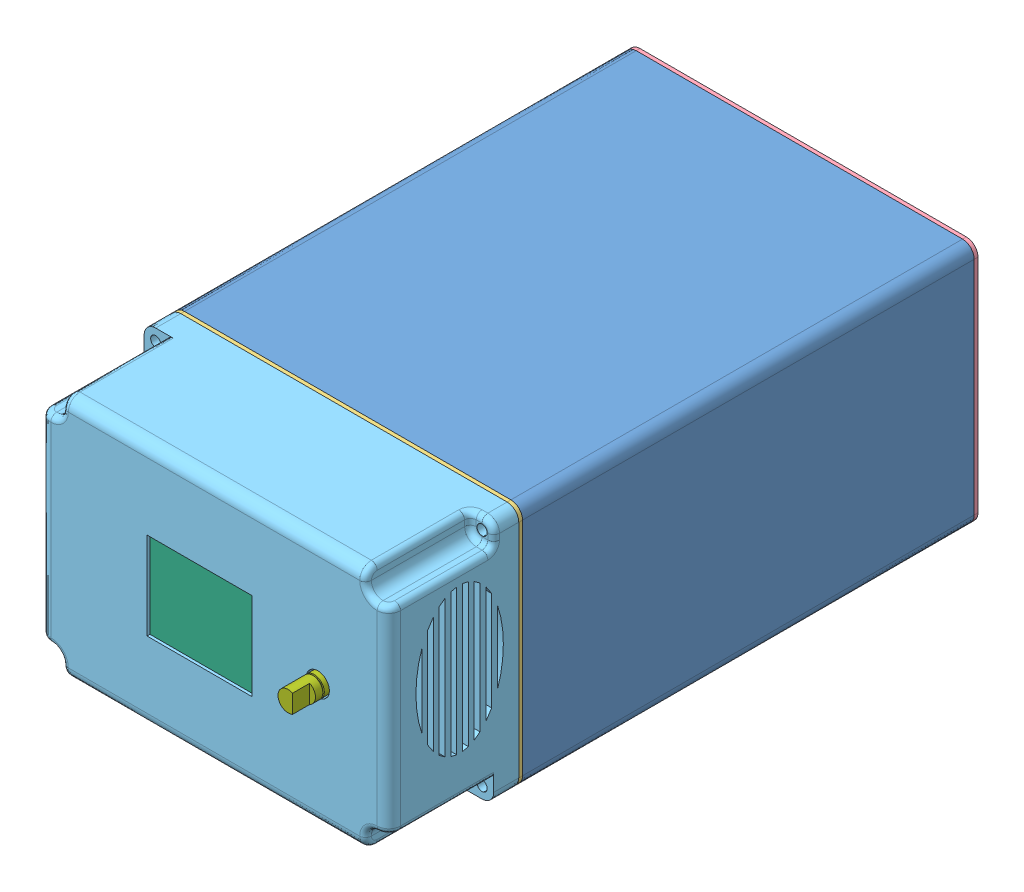
SolidWorks assembly Assembly, configuration Default. Lengths in mm.
Overall size (120 84 212.37).
86 component instances, 26 part files, 29 mates.
Components (placement in the parent):
- ProjectBox-1: ProjectBox [Default] at (98.818 101.4057 83.4216) size (120 84 155)
- Heater700W-1: Heater700W [Default] at (98.818 110.9057 242.9216) x (1 0 0) z (0 0 -1) size (43.19 37.4 149.1)
- SidePlate1-1: SidePlate1 [Default] at (98.818 101.4057 238.4216) x (1 0 0) z (0 -1 0) size (120 1.3 84)
- SidePlate2-1: SidePlate2 [Default] at (98.818 101.4057 82.1216) x (1 0 0) z (0 -1 0) size (120 1.3 84)
- Fan_Assembly-1: Fan_Assembly [По умолчанию] at (98.818 110.6057 93.4216) x (1 0 0) z (0 -1 0) size (62.65 20.13 63.06)
  - Fan_Case-1: Fan_Case [По умолчанию] at origin size (60 20.13 60)
  - Fan-1: Fan [По умолчанию] at (0 -5 0) size (62.65 17 63.06)
- ReflowControllerREV1-1: ReflowControllerREV1 [Default] at (316.3869 204.5107 265.7216) x (-1 0 0) z (0 0 -1) size (81.15 60.96 18.6)
  - ReflowControllerREV1.step-1: ReflowControllerREV1.step [Default] at origin size (81.15 60.96 18.6)
    - R_Axial_DIN0207_L6.3mm_D2.5mm_P10.16mm_Horizontal.step-1: R_Axial_DIN0207_L6.3mm_D2.5mm_P10.16mm_Horizontal.step [Default] at (251.46 -86.995 1.65) x (-1 0 0) z (0 0 1) size (10.76 2.5 5.5)
      - SOLID.step-1: SOLID.step [Default] at origin size (10.76 2.5 5.5)
    - R_Axial_DIN0207_L6.3mm_D2.5mm_P10.16mm_Horizontal.step-2: R_Axial_DIN0207_L6.3mm_D2.5mm_P10.16mm_Horizontal.step [Default] at (251.46 -83.185 1.65) x (-1 0 0) z (0 0 1) size (10.76 2.5 5.5)
      - SOLID.step-1: SOLID.step [Default] at origin size (10.76 2.5 5.5)
    - Terminal5mmx2.step-1: Terminal5mmx2.step [Default] at (255.095 -100.155 1.65) x (1 0 0) z (0 -1 0) size (8.15 13.5 10.57)
      - SOLID-0.step-1: SOLID-0.step [Default] at origin size (8.15 13.5 10.57)
    - Terminal5mmx2.step-2: Terminal5mmx2.step [Default] at (255.595 -113.49 1.65) x (1 0 0) z (0 -1 0) size (8.15 13.5 10.57)
      - SOLID-0.step-1: SOLID-0.step [Default] at origin size (8.15 13.5 10.57)
    - PinSocket_1x08_P2.54mm_Horizontal.step-1: PinSocket_1x08_P2.54mm_Horizontal.step [Default] at (185.42 -121.92 -0.05) x (1 0 0) z (0 0 -1) size (10.13 20.32 5.84)
      - SOLID-1.step-1: SOLID-1.step [Default] at origin size (10.13 20.32 5.84)
    - PinSocket_1x05_P2.54mm_Horizontal.step-1: PinSocket_1x05_P2.54mm_Horizontal.step [Default] at (185.42 -95.25 -0.05) x (1 0 0) z (0 0 -1) size (10.13 12.7 5.84)
      - SOLID-2.step-1: SOLID-2.step [Default] at origin size (10.13 12.7 5.84)
    - SOIC-8_3,9x4,9.step-1: SOIC-8_3,9x4,9.step [Default] at (213.36 -82.804 1.65) x (0 1 0) z (0 0 1) size (4.9 6 1.75)
      - SOLID-3.step-1: SOLID-3.step [Default] at origin size (4.9 6 1.75)
    - DIP-6_W7.62mm.step-1: DIP-6_W7.62mm.step [Default] at (234.95 -91.948 1.65) x (-1 0 0) z (0 0 1) size (7.87 7.05 6.98)
      - SOLID-4.step-1: SOLID-4.step [Default] at origin size (7.87 7.05 6.98)
    - Arduino_nano.step-1: Arduino_nano.step [Default] at (192.024 -90.932 3.15) x (0 -1 0) z (-1 0 0) size (45.01 18.6 18)
      - COMPOUND.step-1: COMPOUND.step [Default] at origin size (45.01 18.6 18)
    - PinHeader_1x02_P2.54mm_Vertical.step-1: PinHeader_1x02_P2.54mm_Vertical.step [Default] at (198.12 -75.692 1.65) x (0 1 0) z (0 0 1) size (2.54 5.08 11.54)
      - SOLID-5.step-1: SOLID-5.step [Default] at origin size (2.54 5.08 11.54)
    - C_Elec_4x5.8.step-1: C_Elec_4x5.8.step [Default] at (203.2 -83.312 1.65) size (5.74 5.46 5.8)
      - COMPOUND-6.step-1: COMPOUND-6.step [Default] at origin size (5.74 5.46 5.8)
    - C_0805_2012Metric.step-1: C_0805_2012Metric.step [Default] at (204.216 -91.948 1.65) x (0 -1 0) z (0 0 1) size (2 1.25 1.25)
      - SOLID-7.step-1: SOLID-7.step [Default] at origin size (2 1.25 1.25)
    - C_0805_2012Metric.step-2: C_0805_2012Metric.step [Default] at (238.252 -96.012 1.65) x (0 1 0) z (0 0 1) size (2 1.25 1.25)
      - SOLID-7.step-1: SOLID-7.step [Default] at origin size (2 1.25 1.25)
    - C_0805_2012Metric.step-3: C_0805_2012Metric.step [Default] at (219.456 -77.216 1.65) x (0 -1 0) z (0 0 1) size (2 1.25 1.25)
      - SOLID-7.step-1: SOLID-7.step [Default] at origin size (2 1.25 1.25)
    - C_Elec_4x5.8.step-2: C_Elec_4x5.8.step [Default] at (223.012 -82.296 1.65) x (-1 0 0) z (0 0 1) size (5.74 5.46 5.8)
      - COMPOUND-6.step-1: COMPOUND-6.step [Default] at origin size (5.74 5.46 5.8)
    - D_DO-41_SOD81_P10.16mm_Horizontal.step-1: D_DO-41_SOD81_P10.16mm_Horizontal.step [Default] at (212.344 -87.884 1.65) size (10.96 2.72 5.71)
      - SOLID-8.step-1: SOLID-8.step [Default] at origin size (10.96 2.72 5.71)
    - DIP-6_W7.62mm.step-2: DIP-6_W7.62mm.step [Default] at (227.584 -105.664 1.65) size (7.87 7.05 6.98)
      - SOLID-4.step-1: SOLID-4.step [Default] at origin size (7.87 7.05 6.98)
    - JST_EH_B2B-EH-A_1x02_P2.50mm_Vertical.step-1: JST_EH_B2B-EH-A_1x02_P2.50mm_Vertical.step [Default] at (210.82 -75.692 1.65) size (7.5 3.8 9.2)
      - SOLID-9.step-1: SOLID-9.step [Default] at origin size (7.5 3.8 9.2)
    - PinHeader_1x02_P2.54mm_Vertical.step-2: PinHeader_1x02_P2.54mm_Vertical.step [Default] at (223.012 -75.692 1.65) x (0 1 0) z (0 0 1) size (2.54 5.08 11.54)
      - SOLID-5.step-1: SOLID-5.step [Default] at origin size (2.54 5.08 11.54)
    - R_0805_2012Metric.step-1: R_0805_2012Metric.step [Default] at (214.376 -94.488 1.65) x (-1 0 0) z (0 0 1) size (2 1.2 0.45)
      - SOLID-10.step-1: SOLID-10.step [Default] at origin size (2 1.2 0.45)
    - R_0805_2012Metric.step-2: R_0805_2012Metric.step [Default] at (216.916 -91.44 1.65) size (2 1.2 0.45)
      - SOLID-10.step-1: SOLID-10.step [Default] at origin size (2 1.2 0.45)
    - R_0805_2012Metric.step-3: R_0805_2012Metric.step [Default] at (241.3 -99.568 1.65) size (2 1.2 0.45)
      - SOLID-10.step-1: SOLID-10.step [Default] at origin size (2 1.2 0.45)
    - R_0805_2012Metric.step-4: R_0805_2012Metric.step [Default] at (238.252 -103.632 1.65) x (0 1 0) z (0 0 1) size (2 1.2 0.45)
      - SOLID-10.step-1: SOLID-10.step [Default] at origin size (2 1.2 0.45)
    - R_0805_2012Metric.step-5: R_0805_2012Metric.step [Default] at (224.028 -105.664 1.65) size (2 1.2 0.45)
      - SOLID-10.step-1: SOLID-10.step [Default] at origin size (2 1.2 0.45)
    - R_0805_2012Metric.step-6: R_0805_2012Metric.step [Default] at (194.945 -117.475 1.65) x (0 1 0) z (0 0 1) size (2 1.2 0.45)
      - SOLID-10.step-1: SOLID-10.step [Default] at origin size (2 1.2 0.45)
    - R_0805_2012Metric.step-7: R_0805_2012Metric.step [Default] at (197.485 -112.395 -0.05) x (1 0 0) z (0 0 -1) size (2 1.2 0.45)
      - SOLID-10.step-1: SOLID-10.step [Default] at origin size (2 1.2 0.45)
    - R_0805_2012Metric.step-8: R_0805_2012Metric.step [Default] at (203.835 -122.555 1.65) x (-1 0 0) z (0 0 1) size (2 1.2 0.45)
      - SOLID-10.step-1: SOLID-10.step [Default] at origin size (2 1.2 0.45)
    - R_0805_2012Metric.step-9: R_0805_2012Metric.step [Default] at (200.66 -119.38 1.65) size (2 1.2 0.45)
      - SOLID-10.step-1: SOLID-10.step [Default] at origin size (2 1.2 0.45)
    - R_0805_2012Metric.step-10: R_0805_2012Metric.step [Default] at (201.168 -104.648 -0.05) x (1 0 0) z (0 0 -1) size (2 1.2 0.45)
      - SOLID-10.step-1: SOLID-10.step [Default] at origin size (2 1.2 0.45)
    - R_0805_2012Metric.step-11: R_0805_2012Metric.step [Default] at (200.66 -110.236 -0.05) x (1 0 0) z (0 0 -1) size (2 1.2 0.45)
      - SOLID-10.step-1: SOLID-10.step [Default] at origin size (2 1.2 0.45)
    - R_0805_2012Metric.step-12: R_0805_2012Metric.step [Default] at (197.485 -123.19 -0.05) x (-1 0 0) z (0 0 -1) size (2 1.2 0.45)
      - SOLID-10.step-1: SOLID-10.step [Default] at origin size (2 1.2 0.45)
    - R_0805_2012Metric.step-13: R_0805_2012Metric.step [Default] at (195.58 -128.905 -0.05) x (0 -1 0) z (0 0 -1) size (2 1.2 0.45)
      - SOLID-10.step-1: SOLID-10.step [Default] at origin size (2 1.2 0.45)
    - R_0805_2012Metric.step-14: R_0805_2012Metric.step [Default] at (196.215 -114.3 1.65) size (2 1.2 0.45)
      - SOLID-10.step-1: SOLID-10.step [Default] at origin size (2 1.2 0.45)
    - R_0805_2012Metric.step-15: R_0805_2012Metric.step [Default] at (200.66 -115.316 -0.05) x (1 0 0) z (0 0 -1) size (2 1.2 0.45)
      - SOLID-10.step-1: SOLID-10.step [Default] at origin size (2 1.2 0.45)
    - TO-220-3_Horizontal_TabUp.step-1: TO-220-3_Horizontal_TabUp.step [Default] at (244.475 -92.71 -0.05) x (-1 0 0) z (0 0 -1) size (10.25 19.74 12.58)
      - SOLID-11.step-1: SOLID-11.step [Default] at origin size (10.25 19.74 12.58)
    - TO-263-3_TabPin4.step-1: TO-263-3_TabPin4.step [Default] at (218.44 -99.06 -0.05) x (0 -1 0) z (0 0 -1) size (15 10 4.42)
      - SOLID-12.step-1: SOLID-12.step [Default] at origin size (15 10 4.42)
    - COMPOUND-13.step-1: COMPOUND-13.step [Default] at origin size (73.66 60.96 1.6)
- ElectronicsCover-1: ElectronicsCover [Default] at (91.628 101.3957 280.9216) size (120 84 44.6)
- TFT_1.8_128x160-1: TFT_1.8_128x160 [Default] at (91.668 101.3857 279.7216) x (0 -1 0) z (-1 0 0) size (35 3.6 56)
- Encoder-1: Encoder [Default] at (135.788 104.5957 273.6216) x (0 -1 0) z (-1 0 0) size (26.4 20.87 18.5)
- XT-60_Macho-1: XT-60_Macho [Valor predeterminado] at (55.018 70.3339 251.3773) x (0 0 1) z (-1 0 0) size (16.3 8.2 16.2)
Mates (geometry in assembly coordinates):
- Parallel2: parallel aligned: plane of ProjectBox-1 through (98.818 101.4057 238.4216) normal (0 0 1); plane of Heater700W-1 through (98.818 110.9057 242.9216) normal (0 0 1)
- Parallel3: parallel aligned: plane of ProjectBox-1 through (38.818 143.4057 238.4216) normal (0 1 0); plane of Heater700W-1 through (88.0215 129.6057 239.7216) normal (0 1 0)
- Parallel4: parallel aligned: plane of ProjectBox-1 through (98.818 101.4057 238.4216) normal (0 0 1); plane of SidePlate1-1 through (154.818 63.4057 239.7216) normal (0 0 1)
- Coincident11: coincident aligned: plane of ProjectBox-1 through (38.818 143.4057 238.4216) normal (0 1 0); plane of SidePlate1-1 through (42.818 143.4057 239.7216) normal (0 1 0)
- Coincident12: coincident aligned: plane of ProjectBox-1 through (158.818 59.4057 238.4216) normal (1 0 0); plane of SidePlate1-1 through (158.818 63.4057 239.7216) normal (1 0 0)
- Coincident13: coincident anti-aligned: plane of ProjectBox-1 through (98.818 101.4057 238.4216) normal (0 0 1); plane of SidePlate1-1 through (154.818 63.4057 238.4216) normal (0 0 -1)
- Concentric2: concentric aligned: cylinder of Heater700W-1 through (98.818 110.9057 227.5216) axis (0 0 1) radius 15.135; cylinder of SidePlate1-1 through (98.818 110.9057 238.4216) axis (0 0 1) radius 16.25
- Coincident14: coincident: line of Heater700W-1 through (109.6144 92.2057 239.7216) axis (-1 0 0); plane of SidePlate1-1 through (154.818 63.4057 239.7216) normal (0 0 1)
- Coincident18: coincident anti-aligned: plane of ProjectBox-1 through (98.818 101.4057 83.4216) normal (0 0 -1); plane of SidePlate2-1 through (154.818 63.4057 83.4216) normal (0 0 1)
- Coincident19: coincident aligned: plane of ProjectBox-1 through (38.818 59.4057 238.4216) normal (-1 0 0); plane of SidePlate2-1 through (38.818 63.4057 83.4216) normal (-1 0 0)
- Coincident20: coincident aligned: plane of ProjectBox-1 through (38.818 143.4057 238.4216) normal (0 1 0); plane of SidePlate2-1 through (42.818 143.4057 83.4216) normal (0 1 0)
- Concentric3: concentric aligned: cylinder of SidePlate2-1 through (123.818 135.6057 73.4216) axis (0 0 1) radius 1.5; cylinder of Fan_Assembly-1/Fan_Case-1 through (123.818 135.6057 93.4216) axis (0 0 1) radius 2.5
- Concentric4: concentric aligned: cylinder of SidePlate2-1 through (73.818 135.6057 73.4216) axis (0 0 1) radius 1.5; cylinder of Fan_Assembly-1/Fan_Case-1 through (73.818 135.6057 93.4216) axis (0 0 1) radius 2.5
- Coincident21: coincident: line of SidePlate2-1 through (143.818 59.4057 83.4216) axis (0 1 0); plane of Fan_Assembly-1/Fan_Case-1 through (98.818 110.6057 83.4216) normal (0 0 -1)
- Coincident22: coincident anti-aligned: plane of ElectronicsCover-1 through (91.628 101.3957 307.551) normal (0 0 -1); plane of TFT_1.8_128x160-1 through (91.668 101.3857 307.551) normal (0 0 1)
- Coincident23: coincident anti-aligned: plane of ElectronicsCover-1 through (68.818 84.3857 309.951) normal (0 1 0); plane of TFT_1.8_128x160-1 through (68.938 84.3857 309.951) normal (0 -1 0)
- Coincident24: coincident anti-aligned: plane of ElectronicsCover-1 through (114.438 84.3857 309.951) normal (-1 0 0); plane of TFT_1.8_128x160-1 through (114.438 118.3857 309.951) normal (1 0 0)
- Concentric5: concentric aligned: cylinder of ElectronicsCover-1 through (134.438 101.3957 309.951) axis (0 0 -1) radius 4; cylinder of Encoder-1 through (134.438 101.3957 312.201) axis (0 0 -1) radius 3.5
- Concentric6: concentric anti-aligned: cylinder of ElectronicsCover-1 through (143.038 110.3957 301.851) axis (0 0 1) radius 1.75; cylinder of Encoder-1 through (143.038 110.3957 301.851) axis (0 0 -1) radius 1.25
- Coincident25: coincident anti-aligned: plane of ElectronicsCover-1 through (91.628 101.3957 301.851) normal (0 0 -1); plane of Encoder-1 through (135.788 104.5957 301.851) normal (0 0 1)
- Coincident26: coincident anti-aligned: plane of ReflowControllerREV1-1/ReflowControllerREV1.step-1/COMPOUND-13.step-1 through (96.6769 100.3707 265.7216) normal (0 0 1); plane of ElectronicsCover-1 through (127.7919 74.3357 265.7216) normal (0 0 -1)
- Concentric7: concentric aligned: cylinder of ReflowControllerREV1-1/ReflowControllerREV1.step-1/COMPOUND-13.step-1 through (127.7919 126.4057 265.7216) axis (0 0 1) radius 1.905; cylinder of ElectronicsCover-1 through (127.7919 126.4057 265.7216) axis (0 0 1) radius 1.75
- Concentric8: concentric aligned: cylinder of ReflowControllerREV1-1/ReflowControllerREV1.step-1/COMPOUND-13.step-1 through (64.2919 126.4057 265.7216) axis (0 0 1) radius 1.905; cylinder of ElectronicsCover-1 through (64.2919 126.4057 265.7216) axis (0 0 1) radius 1.75
- Coincident27: coincident aligned: plane of ProjectBox-1 through (38.818 143.4057 238.4216) normal (0 1 0); plane of ElectronicsCover-1 through (38.818 143.4057 283.3216) normal (0 1 0)
- Coincident28: coincident aligned: plane of ProjectBox-1 through (158.818 59.4057 238.4216) normal (1 0 0); plane of ElectronicsCover-1 through (158.818 143.4057 283.3216) normal (1 0 0)
- Coincident29: coincident anti-aligned: plane of SidePlate1-1 through (154.818 63.4057 239.7216) normal (0 0 1); plane of ElectronicsCover-1 through (91.628 101.3957 239.7216) normal (0 0 -1)
- Coincident30: coincident: plane of ElectronicsCover-1 through (38.818 70.3339 251.3773) normal (0 0 1); plane of XT-60_Macho-1 through (38.818 78.5339 251.3773) normal (0 0 -1)
- Coincident31: coincident: plane of ElectronicsCover-1 through (38.818 70.3339 266.8773) normal (0 1 0); plane of XT-60_Macho-1 through (38.818 70.3339 251.3773) normal (0 -1 0)
- Coincident32: coincident aligned: plane of ElectronicsCover-1 through (38.818 143.4057 283.3216) normal (-1 0 0); plane of XT-60_Macho-1 through (38.818 70.3339 251.3773) normal (-1 0 0)
